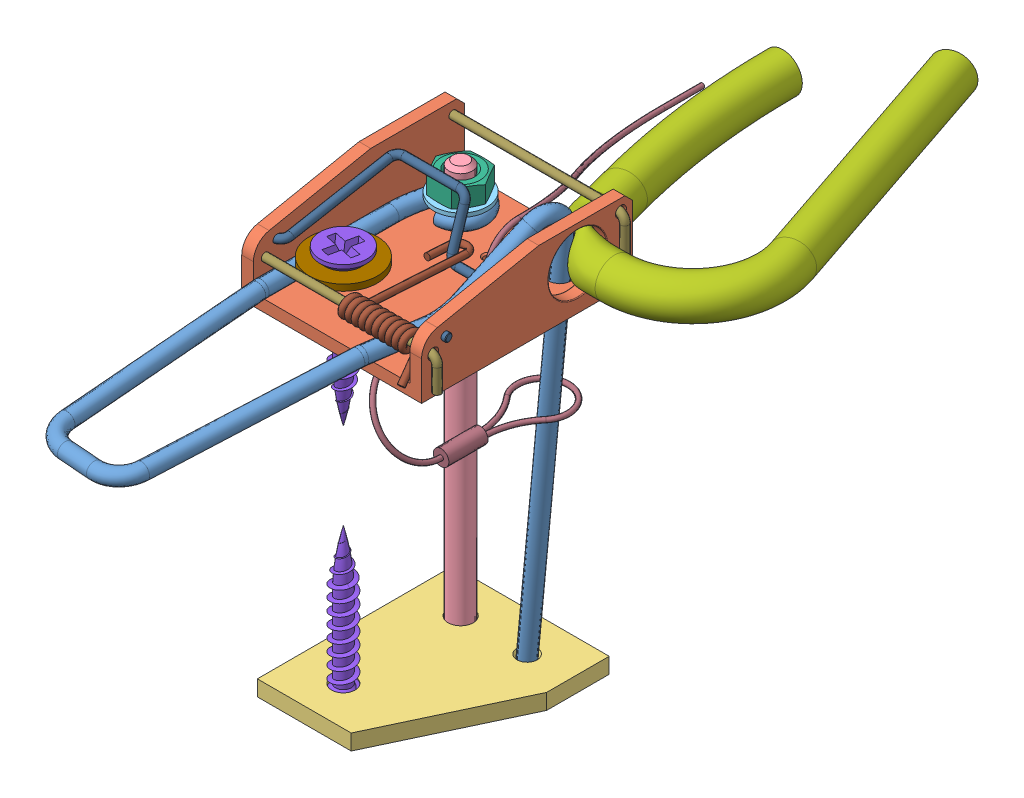
SolidWorks assembly CutOff, configuration Fuel line open. Lengths in mm.
Overall size (119.21 62.02 124).
17 component instances, 14 part files, 40 mates.
Components (placement in the parent):
- Spring-1: Spring [Fuel line open] at origin size (14.06 58.53 54.43)
- BasePlate-1: BasePlate [Default] at (0 -2.5 0) x (0 0 -1) z (1 0 0)
- BottomPlate-1: BottomPlate [Default] at (0 -47.5 0) x (0 0 -1) z (1 0 0)
- Rod-1: Rod [Default] at origin
- M3-washer-1: M3-washer [Default] at (0 1 0)
- M3-washer-2: M3-washer [Default] at (0 -48 0)
- Nut-1: Nut [Default] at (0 1.5 0)
- Nut-2: Nut [Default] at (0 -48 0) x (0.184698 0 -0.982795) z (-0.982795 0 -0.184698)
- FuelTube-1: FuelTube [Open-short] at (18.4 2.5 -4.8) x (-1 0 0) z (0 0 -1) size (27 5.1 47.71)
- LatexTube-1: LatexTube [Default] at (27.2083 -24 -53.077) x (-1 0 0) z (0 0 -1) (hidden)
- WoodScrew-1: WoodScrew [Default] at (0 3 15) x (0.978315 0 0.207122) z (-0.207122 0 0.978315)
- WoodScrew-2: WoodScrew [Default] at (0 -48 15) x (-0.369442 0 0.929254) z (0.929254 0 0.369442)
- M4-washer-1: M4-washer [Default] at (0 1 15)
- Lock-2: Lock [Default] at (13.1739 -0.15 7.5686) x (1 0 0) z (0 0.304167 0.952619)
- LockSpring-1: LockSpring [Down] at (6.8 2.25 20.5) x (1 0 0) z (0 0.058316 0.998298) size (11.73 5.93 18.81)
- TopLock-1: TopLock [Default] at (-5.5 2.25 20.5)
- SaftyWire-1: SaftyWire [Fuel open] at (0 -1.75 0) size (11.69 17.3 49.02)
Mates (geometry in assembly coordinates):
- Coincident3: coincident anti-aligned: plane of Spring-1 through (0 0 0) normal (0 0 1); plane of BasePlate-1 through (0 -2.5 0) normal (0 0 -1)
- Coincident4: coincident aligned: plane of Spring-1 through (0 0 0) normal (1 0 0); plane of BasePlate-1 through (0 -2.5 0) normal (1 0 0)
- Concentric1: concentric aligned: cylinder of BasePlate-1 through (0 -1 0) axis (0 -1 0) radius 1.6; cylinder of BottomPlate-1 through (0 -45.5 0) axis (0 -1 0) radius 1.6
- Concentric2: concentric aligned: cylinder of BasePlate-1 through (0 -1 15) axis (0 -1 0) radius 1.5; cylinder of BottomPlate-1 through (0 -45.5 15) axis (0 -1 0) radius 1.5
- Distance1: distance = 43 mm anti-aligned: plane of BasePlate-1 through (-6 -2.5 22) normal (0 -1 0); plane of BottomPlate-1 through (14 -45.5 20) normal (0 1 0)
- Coincident5: coincident: point of Spring-1; point of Rod-1
- Coincident6: coincident aligned: plane of Spring-1 through (0 0 0) normal (0 0 1); plane of Rod-1 through (0 0 0) normal (0 0 1)
- Coincident7: coincident aligned: plane of Spring-1 through (0 0 0) normal (1 0 0); plane of Rod-1 through (0 0 0) normal (1 0 0)
- Concentric4: concentric aligned: cylinder of Rod-1 through (0 5 0) axis (0 -1 0) radius 1.5; cylinder of M3-washer-1 through (0 1.5 0) axis (0 -1 0) radius 1.6
- Concentric5: concentric aligned: cylinder of Rod-1 through (0 5 0) axis (0 -1 0) radius 1.5; cylinder of M3-washer-2 through (0 -47.5 0) axis (0 -1 0) radius 1.6
- Coincident8: coincident anti-aligned: plane of BottomPlate-1 through (14 -47.5 20) normal (0 -1 0); plane of M3-washer-2 through (0 -47.5 0) normal (0 1 0)
- Distance2: distance = 2 mm anti-aligned: plane of BasePlate-1 through (-6 -1 22) normal (0 1 0); plane of M3-washer-1 through (0 1 0) normal (0 -1 0)
- Concentric6: concentric aligned: cylinder of Rod-1 through (0 5 0) axis (0 -1 0) radius 1.5; cylinder of Nut-1 through (0 4 0) axis (0 -1 0) radius 1.5
- Coincident10: coincident anti-aligned: plane of M3-washer-1 through (0 1.5 0) normal (0 1 0); plane of Nut-1 through (-4.7631 1.5 -2.75) normal (0 -1 0)
- Concentric7: concentric anti-aligned: cylinder of Rod-1 through (0 5 0) axis (0 -1 0) radius 1.5; cylinder of Nut-2 through (0 -50.5 0) axis (0 1 0) radius 1.5
- Coincident11: coincident anti-aligned: plane of M3-washer-2 through (0 -48 0) normal (0 -1 0); plane of Nut-2 through (1.8229 -48 5.1891) normal (0 1 0)
- Distance4: distance = 3.5 mm aligned: plane of BasePlate-1 through (-6 -1 22) normal (0 1 0); plane of FuelTube-1
- Distance5: distance = 1.4 mm anti-aligned: plane of BasePlate-1 through (17 -1 22) normal (1 0 0); plane of FuelTube-1 through (18.4 2.5 -4.8) normal (-1 0 0)
- Distance6: distance = 0.2 mm aligned: plane of BasePlate-1 through (-6 -1 -5) normal (0 0 -1); plane of FuelTube-1 through (18.4 2.5 -4.8) normal (0 0 -1)
- Distance7: distance = 1 mm aligned: plane of Spring-1 through (0 0 0) normal (0 1 0); plane of BasePlate-1 through (-6 -1 22) normal (0 1 0)
- Coincident12: coincident: point of FuelTube-1; point of LatexTube-1
- Concentric8: concentric aligned: cylinder of BasePlate-1 through (0 -1 15) axis (0 -1 0) radius 1.5; cylinder of WoodScrew-1 through (0 3 15) axis (0 -1 0) radius 1
- Coincident16: coincident aligned: cone of BottomPlate-1 through (0 -47.5 15) axis (0 1 0); cone of WoodScrew-2 through (0 -45.5 15) axis (0 1 0)
- Distance8: distance = 2 mm anti-aligned: plane of BasePlate-1 through (-6 -1 22) normal (0 1 0); plane of M4-washer-1 through (0 1 15) normal (0 -1 0)
- Coincident19: coincident aligned: cone of WoodScrew-1 through (0 0.5 15) axis (0 -1 0); cone of M4-washer-1 through (0 1.7 15) axis (0 -1 0)
- Parallel2: parallel aligned: plane of LatexTube-1; plane of assembly
- Parallel3: parallel anti-aligned: plane of LatexTube-1 through (27.2083 -24 -53.077) normal (0 0 -1); plane of assembly
- Concentric9: concentric aligned: cylinder of BasePlate-1 through (15.5 3.5 19) axis (1 0 0) radius 0.5; line of Lock-2 through (17.5 3.5 19) axis (1 0 0)
- Distance9: distance = 0.5 mm: plane of BasePlate-1 through (17 -1 22) normal (1 0 0); point of Lock-2
- Coincident23: coincident: plane of BasePlate-1 through (17 -1 22) normal (1 0 0); point of LockSpring-1
- Concentric11: concentric aligned: cylinder of BasePlate-1 through (-4.5 2.25 20.5) axis (-1 0 0) radius 0.5; cylinder of TopLock-1 through (16.5 2.25 20.5) axis (-1 0 0) radius 0.5
- Concentric12: concentric aligned: cylinder of BasePlate-1 through (-4.5 6 -3.5) axis (-1 0 0) radius 0.5; cylinder of TopLock-1 through (16.5 6 -3.5) axis (-1 0 0) radius 0.5
- Distance10: distance = 5.5 mm: plane of BasePlate-1 through (0 -2.5 0) normal (1 0 0); point of TopLock-1
- Coincident25: coincident anti-aligned: plane of BasePlate-1 through (0 -2.5 0) normal (0 0 -1); plane of SaftyWire-1 through (0 -1.75 0) normal (0 0 1)
- Distance11: distance = 0.75 mm aligned: plane of BasePlate-1; plane of SaftyWire-1 through (0 -1.75 0) normal (0 1 0)
- Coincident27: coincident aligned: plane of BasePlate-1 through (0 -2.5 0) normal (1 0 0); plane of SaftyWire-1 through (0 -1.75 0) normal (1 0 0)
- Distance12: distance = 0.85 mm: plane of BasePlate-1 through (-6 -1 22) normal (0 1 0); point of Lock-2
- Distance13: distance = 4.8 mm: plane of BasePlate-1 through (-6 -1 22) normal (0 1 0); point of Lock-2
- Concentric13: concentric anti-aligned: line of LockSpring-1 through (17 2.25 20.5) axis (1 0 0); cylinder of TopLock-1 through (16.5 2.25 20.5) axis (-1 0 0) radius 0.5
- Angle1: planar angle = 0.767945 rad aligned: plane of BasePlate-1 through (-6 -1 22) normal (0 0 1); plane of LockSpring-1 through (15.0882 -1.2023 22.6896) normal (0.134061 -0.6816 0.71934)
